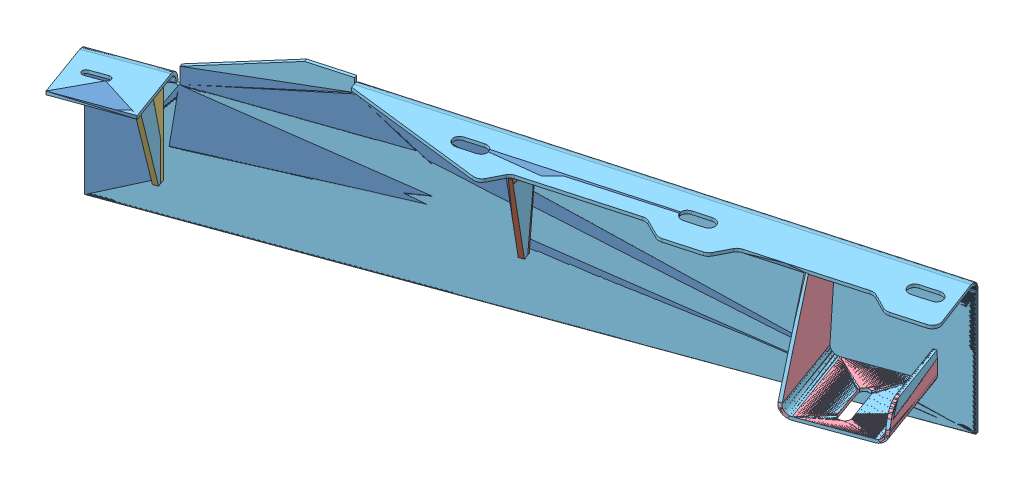
SolidWorks assembly DO597545_STP-_, configuration Výchozí. Lengths in mm.
Overall size (416.99 102.95 186.93).
5 component instances, 5 part files, 0 mates.
Components (placement in the parent):
- DO597546, PLECH OKOPOV_X2_00DD_X0_-1: DO597546, PLECH OKOPOV_X2_00DD_X0_ [Výchozí] at origin size (416.99 102.95 186.93)
- DO597548, PLECH OKOPOV_X2_00DD_X0_-1: DO597548, PLECH OKOPOV_X2_00DD_X0_ [Výchozí] at (-520.1423 12.1795 3156.048) x (-0.340667 0.022175 -0.939923) z (-0.064968 -0.997887 0.000005) size (24.83 3 62)
- DO597547, _X2_017D_X0_EBRO-1: DO597547, _X2_017D_X0_EBRO [Výchozí] at (-689.5471 -3.5 3217.7075) x (0.93969 0 -0.342026) z (0 -1 0) size (3 25 60)
- DO601076, PLECH OKOPOV_X2_00DD_X0_-1: DO601076, PLECH OKOPOV_X2_00DD_X0_ [Výchozí] at (-361.7543 -62.4996 3098.3984) x (0.342026 0 0.93969) z (0.01368 -0.999894 -0.004979) size (50.51 54 66.13)
- DO597545_W, PLECH OKOPOV_X2_00DD_X0_-SVA_X2_0158_X0_ENEC-1: DO597545_W, PLECH OKOPOV_X2_00DD_X0_-SVA_X2_0158_X0_ENEC [Výchozí] at origin size (416.99 102.95 186.93)
